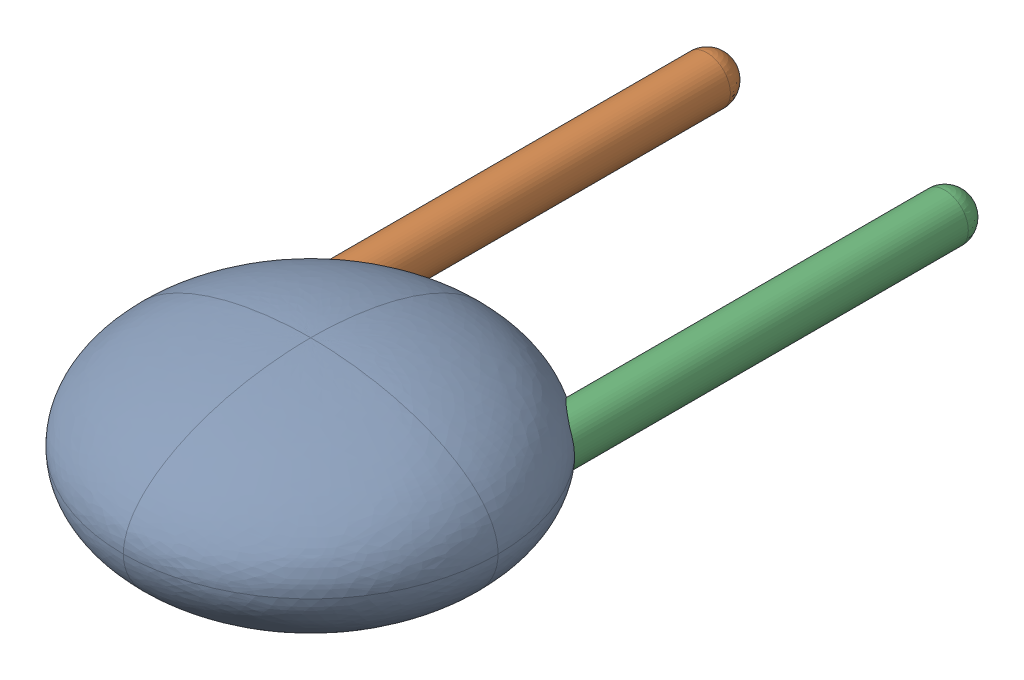
SolidWorks assembly C7, configuration Défaut. Lengths in mm.
Overall size (4 2 7.75).
4 component instances, 3 part files, 0 mates.
Components (placement in the parent):
- Open CASCADE STEP translator 6.8 1.3.1-1: Open CASCADE STEP translator 6.8 1.3.1 [Défaut] at origin size (4 2 7.75)
  - Body_1_2-1: Body_1_2 [Défaut] at (1.27 -1.27 0) x (0 1 0) z (0 0 1) size (2 4 4)
  - Pin_1-1: Pin_1 [Défaut] x (0 -1 0) z (0 0 1) size (0.5 0.5 5.5)
  - Pin_2-1: Pin_2 [Défaut] at (2.54 2.54 0) x (0 -1 0) z (0 0 1) size (0.5 0.5 5.5)
